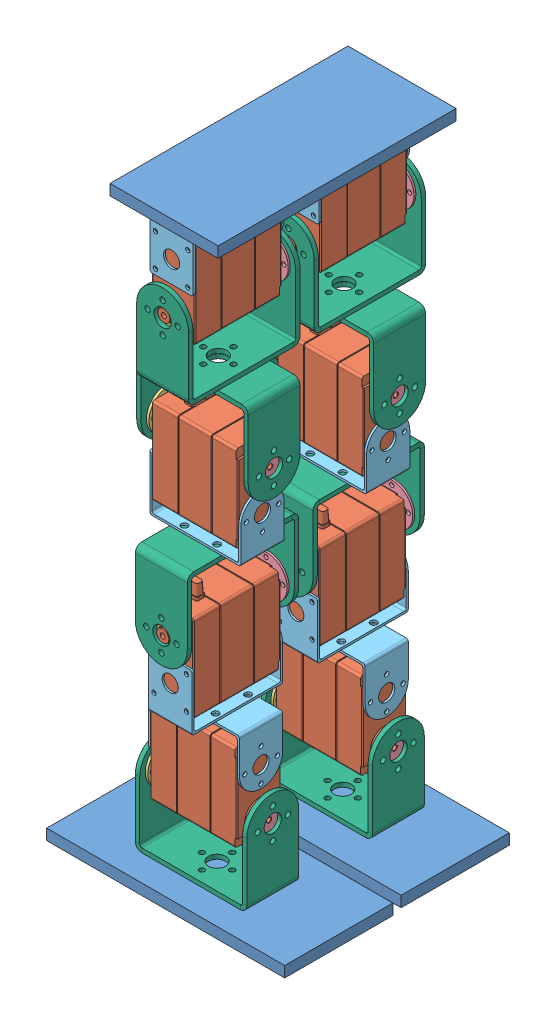
SolidWorks assembly AssemFinal, configuration Default. Lengths in mm.
Overall size (111.2 279.68 110.17).
53 component instances, 6 part files, 12 mates.
Components (placement in the parent):
- base-plate-1: base-plate [Default] at origin size (50 5 110)
- Leg 1-3: Leg 1 [Default] at (-101.665 -81.9924 33.8411) x (0 0 -1) z (1 0 0) size (51.53 269.48 51.53)
  - Assembly-1: Assembly [Default] at (24.006 72.7387 32.0964) x (0 -1 0) z (0 0 1) size (67.3 51.5 26.87)
    - dual shaft servo-1: dual shaft servo [Predeterminado] at (14.992 2.8195 38.2318) size (46.51 48.8 20.07)
    - accessory 1-1: accessory 1 [Predeterminado] at (35.7217 1.0691 58.2951) x (0.70399 0 0.71021) z (0.71021 0 -0.70399) size (19 2.2 19)
    - accessory 2-2: accessory 2 [Predeterminado] at (7.8921 46.4181 29.4135) x (-0.683613 0 -0.729844) z (0.729844 0 -0.683613) size (19 3.2 19)
    - support 1 ( dimensions check)-1: support 1 ( dimensions check) [Predeterminado] at (-9.1537 29.6478 38.798) x (0 1 0) z (0 0 -1) size (42 26 20)
    - U Bracket-1: U Bracket [Défaut] at (58.1419 23.5615 38.2647) x (0 -1 0) z (0 0 -1) size (51.5 42 24)
  - Assembly-2: Assembly [Default] at (9.3028 -43.6451 46.7996) x (0 1 0) z (1 0 0) size (67.3 51.5 26.87)
    - dual shaft servo-1: dual shaft servo [Predeterminado] at (14.992 2.8195 38.2318) size (46.51 48.8 20.07)
    - accessory 1-1: accessory 1 [Predeterminado] at (35.7217 1.0691 58.2951) x (0.70399 0 0.71021) z (0.71021 0 -0.70399) size (19 2.2 19)
    - accessory 2-2: accessory 2 [Predeterminado] at (7.8921 46.4181 29.4135) x (-0.683613 0 -0.729844) z (0.729844 0 -0.683613) size (19 3.2 19)
    - support 1 ( dimensions check)-1: support 1 ( dimensions check) [Predeterminado] at (-9.1537 29.6478 38.798) x (0 1 0) z (0 0 -1) size (42 26 20)
    - U Bracket-1: U Bracket [Défaut] at (58.1419 23.5615 38.2647) x (0 -1 0) z (0 0 -1) size (51.5 42 24)
  - Assembly-3: Assembly [Default] at (24.0393 -111.0408 107.9997) x (0 1 0) z (0 0 -1) size (67.3 51.5 26.87)
    - dual shaft servo-1: dual shaft servo [Predeterminado] at (14.992 2.8195 38.2318) size (46.51 48.8 20.07)
    - accessory 1-1: accessory 1 [Predeterminado] at (35.7217 1.0691 58.2951) x (0.70399 0 0.71021) z (0.71021 0 -0.70399) size (19 2.2 19)
    - accessory 2-2: accessory 2 [Predeterminado] at (7.8921 46.4181 29.4135) x (-0.683613 0 -0.729844) z (0.729844 0 -0.683613) size (19 3.2 19)
    - support 1 ( dimensions check)-1: support 1 ( dimensions check) [Predeterminado] at (-9.1537 29.6478 38.798) x (0 1 0) z (0 0 -1) size (42 26 20)
    - U Bracket-1: U Bracket [Défaut] at (58.1419 23.5615 38.2647) x (0 -1 0) z (0 0 -1) size (51.5 42 24)
  - Assembly-4: Assembly [Default] at (85.2726 -129.4482 46.7664) x (0 -1 0) z (-1 0 0) size (67.3 51.5 26.87)
    - dual shaft servo-1: dual shaft servo [Predeterminado] at (14.992 2.8195 38.2318) size (46.51 48.8 20.07)
    - accessory 1-1: accessory 1 [Predeterminado] at (35.7217 1.0691 58.2951) x (0.70399 0 0.71021) z (0.71021 0 -0.70399) size (19 2.2 19)
    - accessory 2-2: accessory 2 [Predeterminado] at (7.8921 46.4181 29.4135) x (-0.683613 0 -0.729844) z (0.729844 0 -0.683613) size (19 3.2 19)
    - support 1 ( dimensions check)-1: support 1 ( dimensions check) [Predeterminado] at (-9.1537 29.6478 38.798) x (0 1 0) z (0 0 -1) size (42 26 20)
    - U Bracket-1: U Bracket [Défaut] at (58.1419 23.5615 38.2647) x (0 -1 0) z (0 0 -1) size (51.5 42 24)
- Leg 1-4: Leg 1 [Default] at (-101.9011 -81.9924 91.6799) x (0 0 -1) z (1 0 0) size (51.53 269.48 51.53)
  - Assembly-1: Assembly [Default] at (24.006 72.7387 32.0964) x (0 -1 0) z (0 0 1) size (67.3 51.5 26.87)
    - dual shaft servo-1: dual shaft servo [Predeterminado] at (14.992 2.8195 38.2318) size (46.51 48.8 20.07)
    - accessory 1-1: accessory 1 [Predeterminado] at (35.7217 1.0691 58.2951) x (0.70399 0 0.71021) z (0.71021 0 -0.70399) size (19 2.2 19)
    - accessory 2-2: accessory 2 [Predeterminado] at (7.8921 46.4181 29.4135) x (-0.683613 0 -0.729844) z (0.729844 0 -0.683613) size (19 3.2 19)
    - support 1 ( dimensions check)-1: support 1 ( dimensions check) [Predeterminado] at (-9.1537 29.6478 38.798) x (0 1 0) z (0 0 -1) size (42 26 20)
    - U Bracket-1: U Bracket [Défaut] at (58.1419 23.5615 38.2647) x (0 -1 0) z (0 0 -1) size (51.5 42 24)
  - Assembly-2: Assembly [Default] at (9.3028 -43.6451 46.7996) x (0 1 0) z (1 0 0) size (67.3 51.5 26.87)
    - dual shaft servo-1: dual shaft servo [Predeterminado] at (14.992 2.8195 38.2318) size (46.51 48.8 20.07)
    - accessory 1-1: accessory 1 [Predeterminado] at (35.7217 1.0691 58.2951) x (0.70399 0 0.71021) z (0.71021 0 -0.70399) size (19 2.2 19)
    - accessory 2-2: accessory 2 [Predeterminado] at (7.8921 46.4181 29.4135) x (-0.683613 0 -0.729844) z (0.729844 0 -0.683613) size (19 3.2 19)
    - support 1 ( dimensions check)-1: support 1 ( dimensions check) [Predeterminado] at (-9.1537 29.6478 38.798) x (0 1 0) z (0 0 -1) size (42 26 20)
    - U Bracket-1: U Bracket [Défaut] at (58.1419 23.5615 38.2647) x (0 -1 0) z (0 0 -1) size (51.5 42 24)
  - Assembly-3: Assembly [Default] at (24.0393 -111.0408 107.9997) x (0 1 0) z (0 0 -1) size (67.3 51.5 26.87)
    - dual shaft servo-1: dual shaft servo [Predeterminado] at (14.992 2.8195 38.2318) size (46.51 48.8 20.07)
    - accessory 1-1: accessory 1 [Predeterminado] at (35.7217 1.0691 58.2951) x (0.70399 0 0.71021) z (0.71021 0 -0.70399) size (19 2.2 19)
    - accessory 2-2: accessory 2 [Predeterminado] at (7.8921 46.4181 29.4135) x (-0.683613 0 -0.729844) z (0.729844 0 -0.683613) size (19 3.2 19)
    - support 1 ( dimensions check)-1: support 1 ( dimensions check) [Predeterminado] at (-9.1537 29.6478 38.798) x (0 1 0) z (0 0 -1) size (42 26 20)
    - U Bracket-1: U Bracket [Défaut] at (58.1419 23.5615 38.2647) x (0 -1 0) z (0 0 -1) size (51.5 42 24)
  - Assembly-4: Assembly [Default] at (85.2726 -129.4482 46.7664) x (0 -1 0) z (-1 0 0) size (67.3 51.5 26.87)
    - dual shaft servo-1: dual shaft servo [Predeterminado] at (14.992 2.8195 38.2318) size (46.51 48.8 20.07)
    - accessory 1-1: accessory 1 [Predeterminado] at (35.7217 1.0691 58.2951) x (0.70399 0 0.71021) z (0.71021 0 -0.70399) size (19 2.2 19)
    - accessory 2-2: accessory 2 [Predeterminado] at (7.8921 46.4181 29.4135) x (-0.683613 0 -0.729844) z (0.729844 0 -0.683613) size (19 3.2 19)
    - support 1 ( dimensions check)-1: support 1 ( dimensions check) [Predeterminado] at (-9.1537 29.6478 38.798) x (0 1 0) z (0 0 -1) size (42 26 20)
    - U Bracket-1: U Bracket [Défaut] at (58.1419 23.5615 38.2647) x (0 -1 0) z (0 0 -1) size (51.5 42 24)
- base-plate-2: base-plate [Default] at (-16.8503 -274.6825 18.7027) x (0 0 1) z (-1 0 0) size (50 5 110)
- base-plate-3: base-plate [Default] at (-46.9629 -274.6825 13.6286) x (0 0 -1) z (1 0 0) size (50 5 110)
Mates (geometry in assembly coordinates):
- Parallel2: parallel anti-aligned: plane of base-plate-1 through (0 0 0) normal (0 -1 0); plane of Leg 1-3/Assembly-1/support 1 ( dimensions check)-1 through (-30.7706 -0.1 -19.8127) normal (0 1 0)
- Lock8: lock: unknown of base-plate-1; unknown of Leg 1-3/Assembly-1/support 1 ( dimensions check)-1
- Perpendicular3: perpendicular: plane of base-plate-1 through (-55.0578 5 -39.3425) normal (0 0 -1); line of Leg 1-3/Assembly-1/support 1 ( dimensions check)-1 through (-41.2706 -0.1 6.9007) axis (0 0 -1)
- Parallel3: parallel anti-aligned: plane of base-plate-1 through (0 0 0) normal (0 -1 0); plane of Leg 1-4/Assembly-1/support 1 ( dimensions check)-1 through (-31.0067 -0.1 38.0261) normal (0 1 0)
- Lock7: lock: unknown of base-plate-1; unknown of Leg 1-4/Assembly-1/support 1 ( dimensions check)-1
- Perpendicular5: perpendicular: plane of base-plate-1 through (-55.0578 5 -39.3425) normal (-1 0 0); plane of Leg 1-4/Assembly-1/support 1 ( dimensions check)-1 through (-31.0067 -0.1 23.7375) normal (0 0 -1)
- Parallel4: parallel anti-aligned: plane of Leg 1-3/Assembly-4/U Bracket-1 through (-5.5871 -269.5825 -25.1667) normal (0 -1 0); plane of base-plate-2 through (-16.8503 -269.6825 18.7027) normal (0 1 0)
- Lock4: lock: unknown of ?; unknown of base-plate-2
- Parallel5: parallel aligned: plane of Leg 1-3/Assembly-4/U Bracket-1 through (-55.0871 -266.5825 -25.1667) normal (0 0 -1); plane of base-plate-2 through (22.4922 -269.6825 -36.3552) normal (0 0 -1)
- Parallel6: parallel anti-aligned: plane of Leg 1-4/Assembly-4/U Bracket-1 through (-5.8232 -269.5825 32.6721) normal (0 -1 0); plane of base-plate-3 through (-46.9629 -269.6825 13.6286) normal (0 1 0)
- Lock5: lock: unknown of ?; unknown of base-plate-3
- Perpendicular8: perpendicular: line of Leg 1-4/Assembly-4/U Bracket-1 through (-8.8232 -269.5825 56.6721) axis (-1 0 0); plane of base-plate-3 through (23.6946 -269.6825 68.6864) normal (1 0 0)
